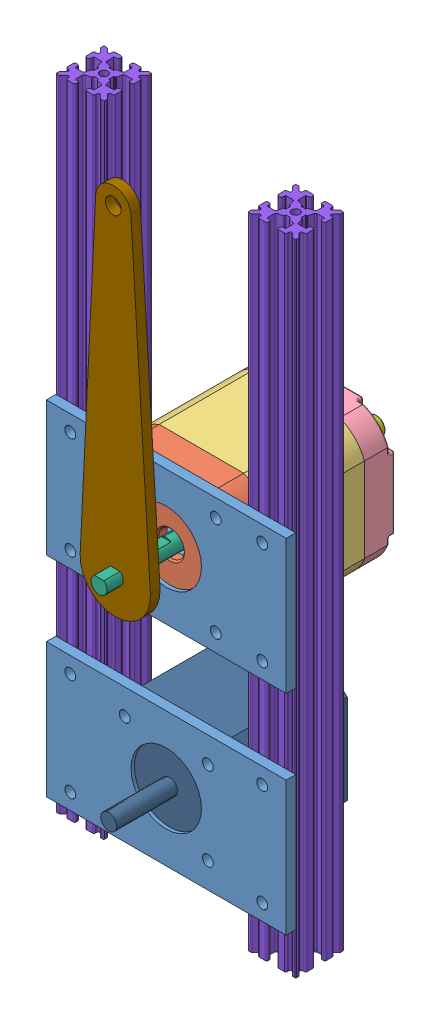
SolidWorks assembly mounted-motor, configuration Default. Lengths in mm.
Overall size (75 207.52 71.95).
17 component instances, 10 part files, 13 mates.
Components (placement in the parent):
- stepper-motor-mounting-plate-1: stepper-motor-mounting-plate [NEMA17] at (-27.6806 15.4361 2.6196) size (75 42 3)
- Nema 17-1: Nema 17 [Default] at (-27.6806 15.4361 2.6196) size (42 42 71.95)
  - Part1^Nema 17-1: Part1^Nema 17 [Default] at origin size (42 42 10.8) (virtual)
  - Part2^Nema 17-1: Part2^Nema 17 [Default] at (0 0 -8) x (-1 0 0) z (0 0 -1) size (42 42 30) (virtual)
  - Part3^Nema 17-1: Part3^Nema 17 [Default] at (0 0 -38) x (-1 0 0) z (0 0 -1) size (42 42 10.2) (virtual)
  - radial ball bearing_68_din-1: radial ball bearing_68_din [DIN 625 - 625 - 8,SI,NC,8_68] at (0 0 -3.7) x (0 0 -1) z (1 0 0) size (5 16 16)
  - radial ball bearing_68_din-2: radial ball bearing_68_din [DIN 625 - 625 - 8,SI,NC,8_68] at (0 0 -41.9) x (0 0 -1) z (0.878806 0.477179 0) size (5 16 16)
  - Part4^Nema 17-1: Part4^Nema 17 [Default] at (0 0 -44.5) x (0.99998 0.006291 0) z (0 0 1) size (5 5 68.5) (virtual)
  - pan head cross recess screw_din-3: pan head cross recess screw_din [ISO 7045 - M3 x 40 - Z --- 30N] at (-15.5 15.5 -48) x (0 0 1) z (-1 0 0) size (42.35 5.6 5.6)
  - pan head cross recess screw_din-4: pan head cross recess screw_din [ISO 7045 - M3 x 40 - Z --- 30N] at (-15.5 -15.5 -48) x (0 0 1) z (-1 0 0) size (42.35 5.6 5.6)
  - pan head cross recess screw_din-5: pan head cross recess screw_din [ISO 7045 - M3 x 40 - Z --- 30N] at (15.5 -15.5 -48) x (0 0 1) z (-1 0 0) size (42.35 5.6 5.6)
  - pan head cross recess screw_din-6: pan head cross recess screw_din [ISO 7045 - M3 x 40 - Z --- 30N] at (15.5 15.5 -48) x (0 0 1) z (-1 0 0) size (42.35 5.6 5.6)
- TL-400-0101-002-1: TL-400-0101-002 [Default] at (-57.6806 23.3338 -4.8804) x (1 0 0) z (0 1 0) size (15 15 200)
- TL-400-0101-002-2: TL-400-0101-002 [Default] at (2.3194 15.8163 -4.8804) x (1 0 0) z (0 1 0) size (15 15 200)
- string arm-1: string arm [Default] at (-27.6806 15.4361 18.5582) x (-0.006291 0.99998 0) z (0 0 1) size (116.5 22 3)
- stepper-motor-mounting-plate-2: stepper-motor-mounting-plate [NEMA14] at (-27.6806 -50.0263 2.6196) size (75 42 3)
- NEMA14-Stepper-Motor-SY35ST36-1: NEMA14-Stepper-Motor-SY35ST36 [Default] at (-27.6806 -50.0263 2.6196) size (35.2 35.2 57)
Mates (geometry in assembly coordinates):
- Concentric1: concentric anti-aligned: cylinder of stepper-motor-mounting-plate-1 through (-27.6806 15.4361 2.6196) axis (0 0 1) radius 11; cylinder of Nema 17-1/Part1^Nema 17-1 through (-27.6806 15.4361 4.4196) axis (0 0 -1) radius 11
- Coincident1: coincident anti-aligned: plane of stepper-motor-mounting-plate-1 through (-27.6806 15.4361 2.6196) normal (0 0 -1); plane of Nema 17-1/Part1^Nema 17-1 through (-27.6806 15.4361 2.6196) normal (0 0 1)
- Coincident2: coincident aligned: plane of stepper-motor-mounting-plate-1 through (-65.1806 -5.5639 5.6196) normal (0 -1 0); plane of Nema 17-1/Part2^Nema 17-1 through (-27.6806 -5.5639 -35.3804) normal (0 -1 0)
- Coincident4: coincident anti-aligned: plane of stepper-motor-mounting-plate-1 through (-27.6806 15.4361 2.6196) normal (0 0 -1); plane of TL-400-0101-002-1 through (-65.1806 123.3338 2.6196) normal (0 0 1)
- Coincident5: coincident aligned: plane of stepper-motor-mounting-plate-1 through (-65.1806 -5.5639 5.6196) normal (-1 0 0); plane of TL-400-0101-002-1 through (-65.1806 123.3338 2.6196) normal (-1 0 0)
- Coincident6: coincident anti-aligned: plane of stepper-motor-mounting-plate-1 through (-27.6806 15.4361 2.6196) normal (0 0 -1); plane of TL-400-0101-002-2 through (-5.1806 115.8163 2.6196) normal (0 0 1)
- Coincident8: coincident aligned: plane of stepper-motor-mounting-plate-1 through (9.8194 -5.5639 5.6196) normal (1 0 0); plane of TL-400-0101-002-2 through (9.8194 115.8163 2.6196) normal (1 0 0)
- Concentric2: concentric anti-aligned: cylinder of Nema 17-1/Part4^Nema 17-1 through (-27.6806 15.4361 26.6196) axis (0 0 -1) radius 2.5; cylinder of string arm-1 through (-27.6806 15.4361 18.5582) axis (0 0 1) radius 2.4
- Parallel1: parallel anti-aligned: plane of Nema 17-1/Part4^Nema 17-1 through (-27.6931 17.436 5.6196) normal (-0.006291 0.99998 0); plane of string arm-1 through (-29.1588 17.3268 18.5582) normal (0.006291 -0.99998 0)
- Coincident9: coincident: plane of stepper-motor-mounting-plate-1 through (9.8194 -5.5639 5.6196) normal (1 0 0); plane of stepper-motor-mounting-plate-2 through (9.8194 -71.0263 5.6196) normal (1 0 0)
- Coincident10: coincident aligned: plane of stepper-motor-mounting-plate-1 through (-27.6806 15.4361 5.6196) normal (0 0 1); plane of stepper-motor-mounting-plate-2 through (-27.6806 -50.0263 5.6196) normal (0 0 1)
- Coincident11: coincident: plane of stepper-motor-mounting-plate-2 through (-27.6806 -50.0263 2.6196) normal (0 0 -1); plane of NEMA14-Stepper-Motor-SY35ST36-1 through (-27.6806 -50.0263 2.6196) normal (0 0 1)
- Concentric3: concentric anti-aligned: cylinder of stepper-motor-mounting-plate-2 through (-27.6806 -50.0263 2.6196) axis (0 0 1) radius 11; cylinder of NEMA14-Stepper-Motor-SY35ST36-1 through (-27.6806 -50.0263 4.6196) axis (0 0 -1) radius 11
